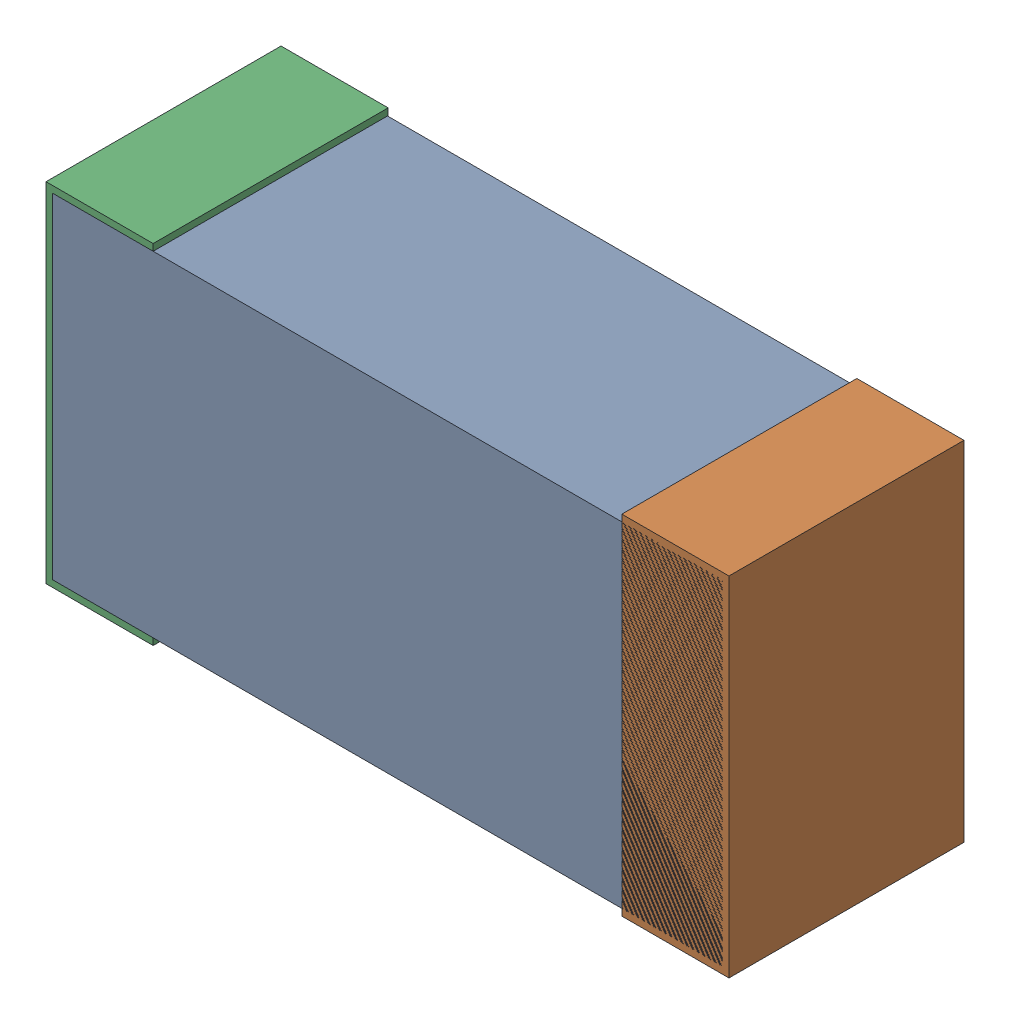
SolidWorks assembly C56, configuration Default. Lengths in mm.
Overall size (1.02 0.52 0.35).
6 component instances, 2 part files, 0 mates.
Components (placement in the parent):
- 870940640-1: 870940640 [Default] at (67.6648 17.219 -1.9506) size (1 0.5 0.35)
  - Extruded_2-1: Extruded_2 [Default] at origin size (1 0.5 0.35)
- 870940480-1: 870940480 [Default] at (68.0948 17.219 -1.9516) size (0.16 0.52 0.35)
  - Extruded-1: Extruded [Default] at origin size (0.16 0.52 0.35)
- 870940480-2: 870940480 [Default] at (67.2348 17.219 -1.9516) size (0.16 0.52 0.35)
  - Extruded-1: Extruded [Default] at origin size (0.16 0.52 0.35)
